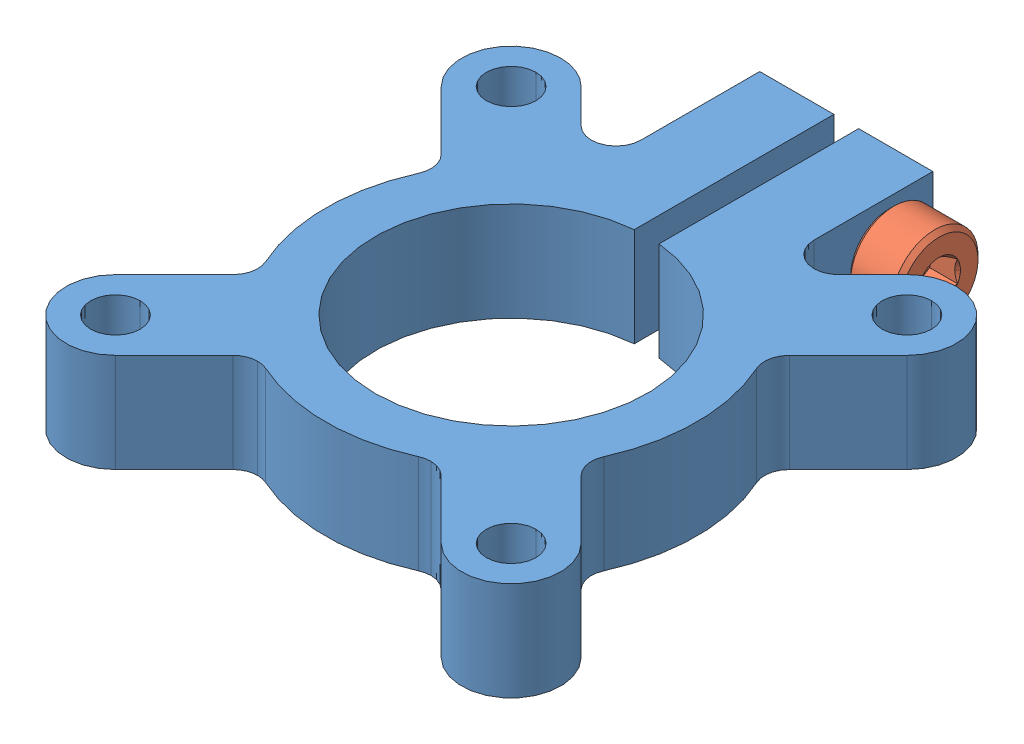
SolidWorks assembly 22mm Clamping Hub 1305-0032-0022, configuration Default. Lengths in mm.
Overall size (40 8 47.1).
2 component instances, 2 part files, 0 mates.
Components (placement in the parent):
- 1305-0032-0022.STEP-1: 1305-0032-0022.STEP [Default] at (-36.9533 17.0148 8.7726) size (40 8 47.1)
- 2800-0004-0014_90128A207.STEP-1: 2800-0004-0014_90128A207.STEP [Default] at (-43.9533 21.0148 -14.8274) x (0 0 1) z (-1 0 0) size (7 7 18.01)
